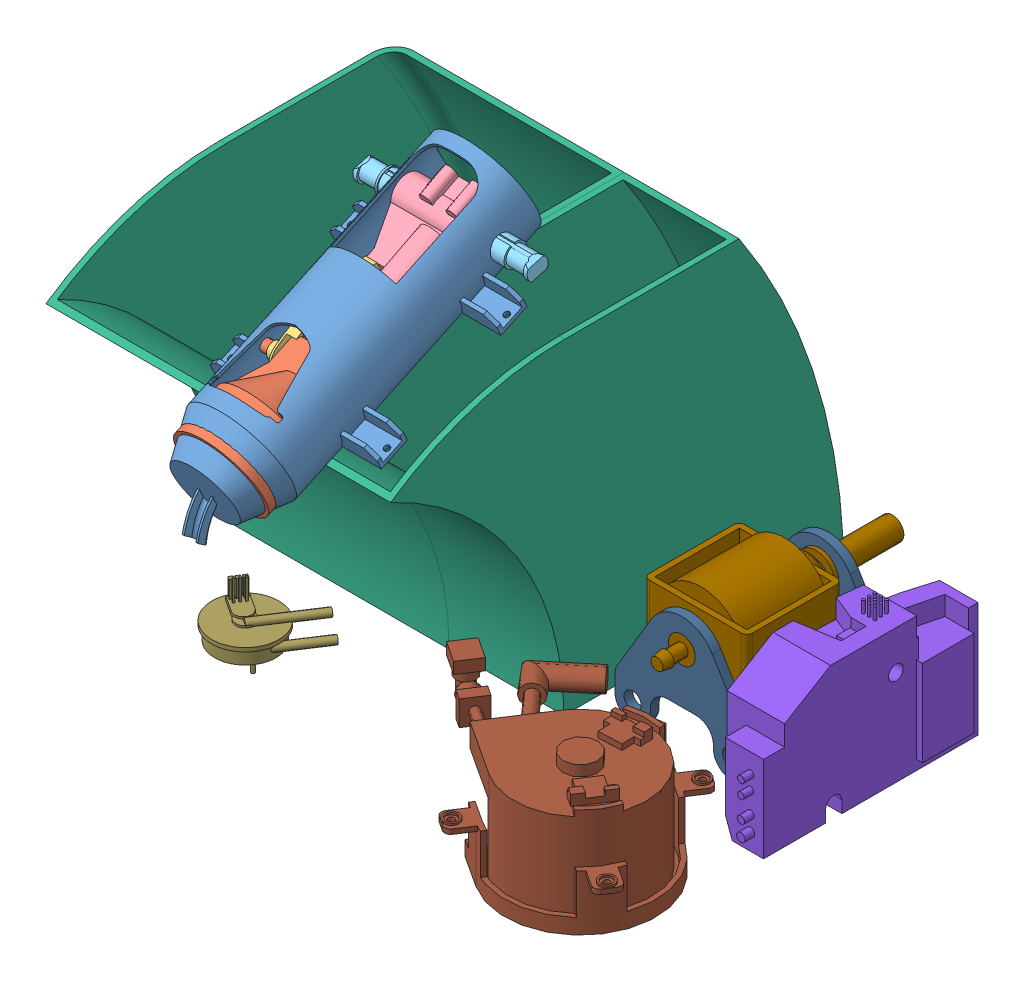
SolidWorks assembly Assembly Koffiezetapparaat ruwe schets Daan de Vries, configuration Default. Lengths in mm.
Overall size (319.3 323.52 370.63).
17 component instances, 13 part files, 14 mates.
Components (placement in the parent):
- Koffiezetapparaat ruwe schets 3-1: Koffiezetapparaat ruwe schets 3 [Default] at (50.1072 73.0688 386.4375) size (304.08 323.48 370.63)
- dispenser-1: dispenser [Default] at (49.5355 307.9898 202.7495) x (1 0 0) z (0 -0.422618 0.906308) size (91 53 176.36)
  - Schenk cilinder-1: Schenk cilinder [Default] at origin size (87.3 53 176.36)
  - Cup crusher-1: Cup crusher [Default] at (26 0 99.7284) x (-1 0 0) z (0 0 1) size (54.82 51.43 61)
  - Arm-1: Arm [right arm] at (9.5 -1.2286 53.7164) x (-1 0 0) z (0 0.975365 0.220596) size (11 57.23 23.97)
  - Arm-2: Arm [Default] at (-9.5 -1.2286 53.7164) x (-1 0 0) z (0 0.975365 0.220596) size (11 57.23 23.97)
  - Pusher-1: Pusher [Default] at (0 -1.3319 56.5531) x (-1 0 0) z (0 0.036414 -0.999337) size (46 35.9 49.33)
  - As-1: As [Default] at (45.4979 0 20) x (0 -0.98643 0.164182) z (-1 0 0) size (13 13 91)
- Waterbakje koffiezetapparaat-1: Waterbakje koffiezetapparaat [Default] at (-39.8928 161.4674 164.391) x (-1 0 0) z (0 0 -1) size (180.79 170 236.43)
- Water entry-1: Water entry [Default] at (-71.4051 78.5652 164.3361) x (1 0 0) z (0 -1 0) size (30.21 45 21.08)
- ECU-1: ECU [Default] at (197.1072 110.5652 165.3825) x (0 0 1) z (0 -1 0) size (117 33 76)
- Assembly Pomp-1: Assembly Pomp [Default] at (163.1689 210.462 193.4642) x (-1 -0.000778 0) z (0.000778 -1 0) size (70.05 123 69.5)
  - Pomp onderdeel-1: Pomp onderdeel [Default] at (46.1667 57.4144 98.8809) size (54 123 56.5)
  - Pomp onderdeel mount-1: Pomp onderdeel mount [Default] at (46.1667 25.4144 124.8809) size (70.05 4.5 61)
  - Pomp onderdeel mount-2: Pomp onderdeel mount [Default] at (46.1667 97.4144 124.8809) size (70.05 4.5 61)
- Hitte element-1: Hitte element [Default] at (145.8759 67.5652 249.8238) x (-0.837169 0 -0.546944) z (-0.546944 0 0.837169) size (131.13 62 104)
- onderdeel koffiezetapparaat-1: onderdeel koffiezetapparaat [Default] at (-40.1984 79.5652 238.7809) x (-0.837169 0 -0.546944) z (0 -1 0) size (35 49.5 29)
Mates (geometry in assembly coordinates):
- Coincident3: coincident aligned: line of Koffiezetapparaat ruwe schets 3-1 through (65.1072 222.5397 357.4405) axis (-1 0 0); line of dispenser-1/Schenk cilinder-1 through (53.6072 222.5397 357.4405) axis (-1 0 0)
- Parallel2: parallel aligned: cylinder of Koffiezetapparaat ruwe schets 3-1 through (50.1072 252.2075 293.8177) axis (0 -0.422618 0.906308) radius 13; cone of dispenser-1/Schenk cilinder-1 through (49.5355 239.5257 349.5714) axis (0 -0.422618 0.906308)
- Distance3: distance = 9.5 mm: plane of dispenser-1/Schenk cilinder-1 through (53.6072 239.5237 349.5705) normal (1 0 0); line of Koffiezetapparaat ruwe schets 3-1 through (63.1072 241.642 316.4754) axis (0 -0.422618 0.906308)
- Coincident4: coincident anti-aligned: plane of Koffiezetapparaat ruwe schets 3-1 through (80.1072 65.5652 369.3912) normal (-1 0 0); plane of Waterbakje koffiezetapparaat-1 through (80.1072 85.5647 192.2508) normal (1 0 0)
- Concentric1: concentric aligned: cylinder of Koffiezetapparaat ruwe schets 3-1 through (200.1072 65.5652 369.3912) axis (-1 0 0) radius 322.9538; cylinder of Waterbakje koffiezetapparaat-1 through (80.1072 65.5652 369.3912) axis (-1 0 0) radius 322.9538
- Coincident5: coincident anti-aligned: plane of Koffiezetapparaat ruwe schets 3-1 through (80.1072 75.5652 61.803) normal (0 1 0); plane of Waterbakje koffiezetapparaat-1 through (80.1072 75.5652 192.6609) normal (0 -1 0)
- Distance4: distance = 20 mm anti-aligned: plane of Water entry-1 through (-56.4051 85.5652 164.3361) normal (0 1 0); plane of Koffiezetapparaat ruwe schets 3-1 through (200.1072 65.5652 300.3843) normal (0 -1 0)
- Distance7: distance = 10 mm aligned: plane of Koffiezetapparaat ruwe schets 3-1 through (200.1072 65.5652 300.3843) normal (0 -1 0); plane of ECU-1 through (197.1072 75.5652 125.3825) normal (0 -1 0)
- Coincident11: coincident aligned: plane of Koffiezetapparaat ruwe schets 3-1 through (200.1072 80.5652 61.803) normal (1 0 0); plane of ECU-1 through (200.1072 110.5652 165.3825) normal (1 0 0)
- Tangent3: tangent aligned: plane of Koffiezetapparaat ruwe schets 3-1 through (200.1072 65.5652 300.3843) normal (0 -1 0); cylinder of Assembly Pomp-1/Pomp onderdeel mount-1 through (91.3578 74.8419 163.5498) axis (0 0 1) radius 9.2767
- Tangent4: tangent aligned: plane of Koffiezetapparaat ruwe schets 3-1 through (200.1072 65.5652 300.3843) normal (0 -1 0); cylinder of Assembly Pomp-1/Pomp onderdeel mount-1 through (142.8578 74.8434 163.5498) axis (0 0 1) radius 9.2781
- Distance11: distance = 10 mm: plane of Assembly Pomp-1/Pomp onderdeel-1 through (90.0917 95.5242 114.0498) normal (-1 -0.000778 0); line of Waterbakje koffiezetapparaat-1 through (80.1072 75.5652 192.6609) axis (0 0 -1)
- Coincident17: coincident aligned: plane of Koffiezetapparaat ruwe schets 3-1 through (200.1072 65.5652 300.3843) normal (0 -1 0); plane of Hitte element-1 through (145.8759 65.5652 249.8238) normal (0 -1 0)
- Coincident18: coincident aligned: plane of Koffiezetapparaat ruwe schets 3-1 through (200.1072 65.5652 300.3843) normal (0 -1 0); plane of onderdeel koffiezetapparaat-1 through (-40.1984 65.5652 238.7809) normal (0 -1 0)
